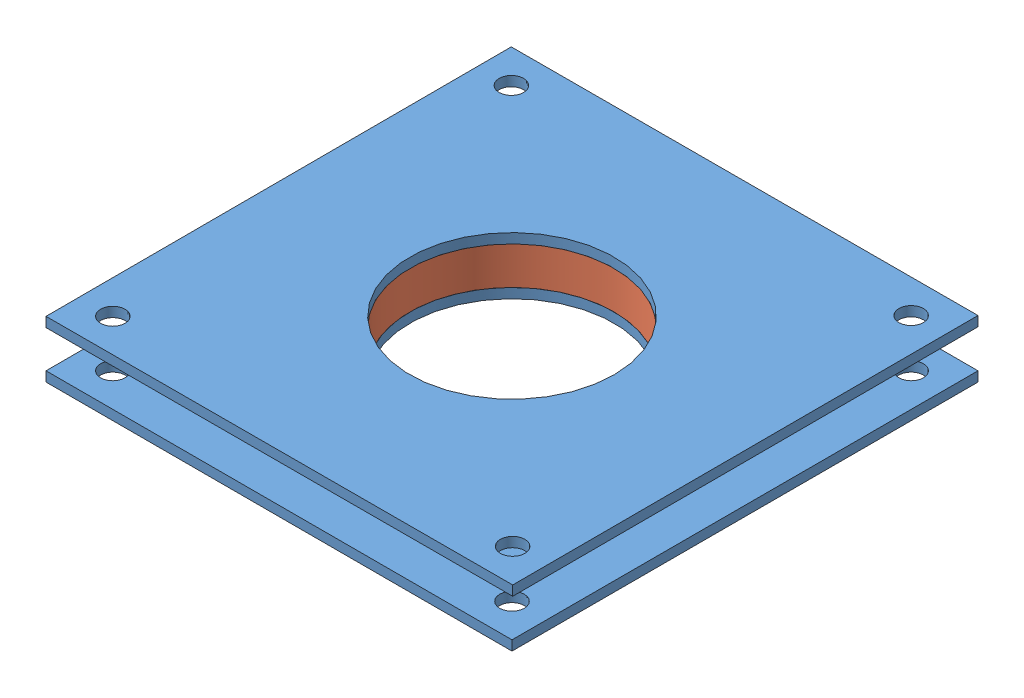
SolidWorks assembly small lazy susan 76mm diameter, configuration Default. Lengths in mm.
Overall size (76.12 9.35 76.12).
3 component instances, 2 part files, 4 mates.
Components (placement in the parent):
- small lazy susan top and bottom-1: small lazy susan top and bottom [Default] at origin size (76 1.6 76)
- small lazy susan bearing mockup-1: small lazy susan bearing mockup [Default] at origin size (53.3 6.15 53.3)
- small lazy susan top and bottom-2: small lazy susan top and bottom [Default] at (0 7.75 0) x (-0.001573 0 -0.999999) z (0.999999 0 -0.001573) size (76 1.6 76)
Mates (geometry in assembly coordinates):
- Coincident1: coincident anti-aligned: plane of small lazy susan top and bottom-1 through (0 0 0) normal (0 1 0); plane of small lazy susan bearing mockup-1 through (0 0 0) normal (0 -1 0)
- Concentric1: concentric aligned: circle of small lazy susan top and bottom-1; circle of small lazy susan bearing mockup-1
- Concentric2: concentric aligned: circle of small lazy susan bearing mockup-1; circle of small lazy susan top and bottom-2
- Coincident4: coincident anti-aligned: plane of small lazy susan bearing mockup-1 through (0 6.15 0) normal (0 1 0); plane of small lazy susan top and bottom-2 through (0 6.15 0) normal (0 -1 0)
